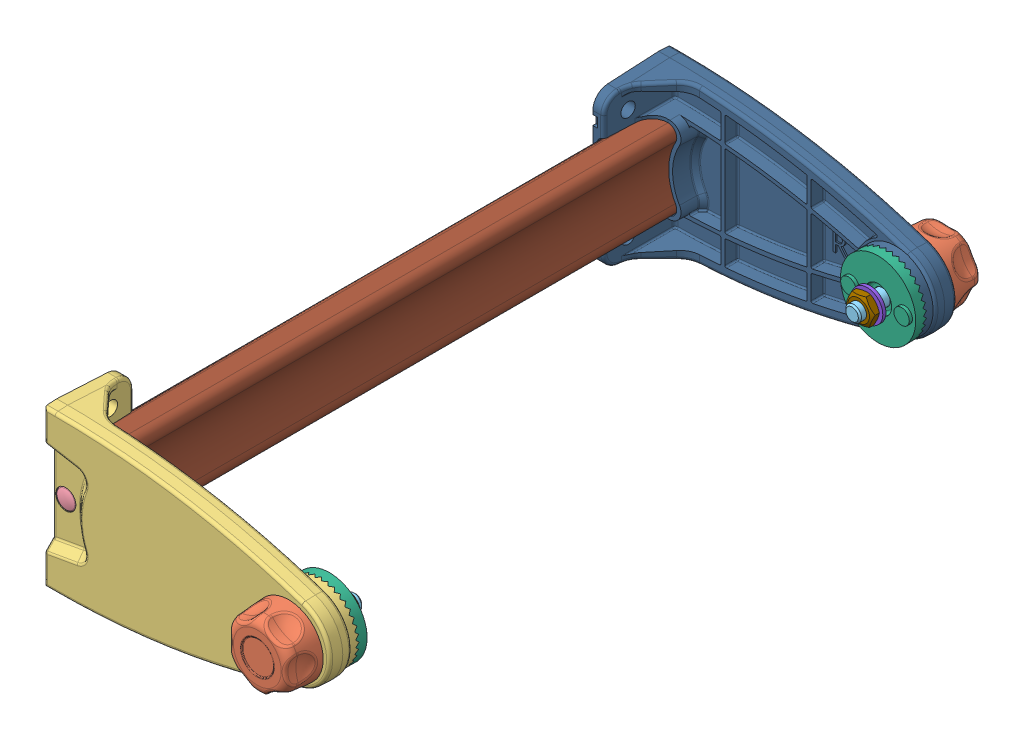
SolidWorks assembly SoportePared_Inferior, configuration Default. Lengths in mm.
Overall size (92.44 51.36 217.6).
23 component instances, 12 part files, 0 mates.
Components (placement in the parent):
- 92815024_AT-0150-7024-UWB.stp-1: 92815024_AT-0150-7024-UWB.stp [Default] at origin size (92.44 51.36 217.6)
  - 1009786_3D.stp-1: 1009786_3D.stp [Default] at (2.5303 -17.4574 8.0327) x (0 1 0) z (0 0 -1) size (23.3 22.5 23.97)
    - DIN16903-R-M5.stp-1: DIN16903-R-M5.stp [Default] at (-1.013 -2.5303 -0.6673) size (8.08 7 10.8)
    - 1009786_3D-0.stp-1: 1009786_3D-0.stp [Default] at (-1.013 -2.5303 -13.1673) size (23.3 22.5 12.5)
  - 1009786_3D.stp-2: 1009786_3D.stp [Default] at (1.013 -15.9401 -186.6327) size (23.3 22.5 23.97)
    - DIN16903-R-M5.stp-1: DIN16903-R-M5.stp [Default] at (-1.013 -2.5303 -0.6673) size (8.08 7 10.8)
    - 1009786_3D-0.stp-1: 1009786_3D-0.stp [Default] at (-1.013 -2.5303 -13.1673) size (23.3 22.5 12.5)
  - 1009783_3D.stp-1: 1009783_3D.stp [Default] at (0 -18.4704 3.7) size (91.25 51.36 25.01)
  - 1009410_3D.stp-1: 1009410_3D.stp [Default] at (-74.3 -18.4704 6.2) x (0.048908 0.998803 0) z (0 0 1) size (6.45 6.45 2.25)
  - 1009785_3D.stp-1: 1009785_3D.stp [Default] at (0 -18.4704 3.9) x (-0.5 -0.866025 0) z (0 0 -1) size (8 9.24 25)
  - 1009784_3D.stp-1: 1009784_3D.stp [Default] at (0 -18.4704 -1.8) x (0 1 0) z (0 0 1) size (24 24 8.2)
  - DIN 3771 - 5 x 1,8 - N - NBR 70(1).stp-1: DIN 3771 - 5 x 1,8 - N - NBR 70(1).stp [Default] at (0 -18.4704 -1.4) x (0 0 -1) z (-0.115782 0.993275 0) size (1.8 8.6 8.6)
  - DIN 125-1 A A 5,3.stp-1: DIN 125-1 A A 5,3.stp [Default] at (0 -18.4704 -4.3) x (0 0 -1) z (-0.412431 0.910989 0) size (1 10 10)
  - DIN 439-2 - ersetzt durch DIN EN 24035_28675 M5.stp-1: DIN 439-2 - ersetzt durch DIN EN 24035_28675 M5.stp [Default] at (0 -18.4704 -8) x (0 0 1) z (-0.075055 0.997179 0) size (2.7 9.24 8)
  - 1009796_3D.stp-1: 1009796_3D.stp [Default] at (0 -18.4704 -182.3) size (91.25 50 25.01)
  - 1009410_3D.stp-2: 1009410_3D.stp [Default] at (-74.3 -18.4704 -184.8) x (-0.469476 -0.882945 0) z (0 0 -1) size (6.45 6.45 2.25)
  - 1009785_3D.stp-2: 1009785_3D.stp [Default] at (0 -18.4704 -182.5) x (0.5 0.866025 0) z (0 0 1) size (8 9.24 25)
  - 1009784_3D.stp-2: 1009784_3D.stp [Default] at (0 -18.4704 -176.8) x (0 -1 0) z (0 0 -1) size (24 24 8.2)
  - DIN 125-1 A A 5,3.stp-2: DIN 125-1 A A 5,3.stp [Default] at (0 -18.4704 -174.3) x (0 0 1) z (-0.179847 0.983695 0) size (1 10 10)
  - DIN 439-2 - ersetzt durch DIN EN 24035_28675 M5.stp-2: DIN 439-2 - ersetzt durch DIN EN 24035_28675 M5.stp [Default] at (0 -18.4704 -170.6) x (0 0 -1) z (0.923859 -0.382734 0) size (2.7 9.24 8)
  - 1002879_185 LANG_3DSYM.stp-1: 1002879_185 LANG_3DSYM.stp [Default] at (-72.0031 -18.4704 -923.3) size (9.99 25.1 185)
  - SHR Z B2,9x22 DIN 7981 mG_3Dsym.stp-1: SHR Z B2,9x22 DIN 7981 mG_3Dsym.stp [Default] at (-421.1883 215.4628 7) x (1 0 0) z (0 0 -1) size (5.6 5.6 24.26)
  - SHR Z B2,9x22 DIN 7981 mG_3Dsym.stp-2: SHR Z B2,9x22 DIN 7981 mG_3Dsym.stp [Default] at (-421.1883 -252.4036 -185.6) size (5.6 5.6 24.26)
